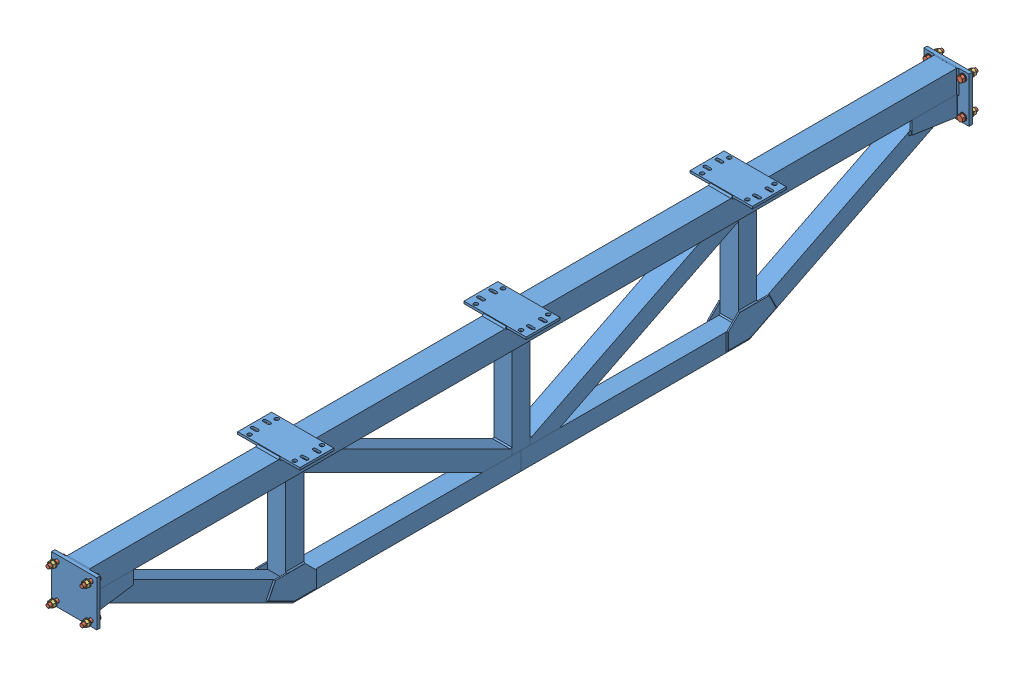
SolidWorks assembly 0404-FRAME 2 ASSEMBLAGE, configuration Predeterminado. Lengths in mm.
Overall size (275 600 3954).
17 component instances, 3 part files, 16 mates.
Components (placement in the parent):
- 0412-FRAME 2-1: 0412-FRAME 2 [Predeterminado<Como mecanizada>] at (105.2462 274.3748 0) size (275 600 3870)
- M-16x60 DIN-6914-18 and DIN-6916-1: M-16x60 DIN-6914-18 and DIN-6916 [DIN 6914 - M20 x 65 x 31-N] at (30.2462 299.3748 1904) x (0 0 1) z (-1 0 0) size (73 30 30)
- M-16x60 DIN-6914-18 and DIN-6916-6: M-16x60 DIN-6914-18 and DIN-6916 [DIN 6914 - M20 x 65 x 31-N] at (180.2462 299.3748 1904) x (0 0 1) z (-1 0 0) size (73 30 30)
- M-16x60 DIN-6914-18 and DIN-6916-8: M-16x60 DIN-6914-18 and DIN-6916 [DIN 6914 - M20 x 65 x 31-N] at (180.2462 149.3748 1904) x (0 0 1) z (-1 0 0) size (73 30 30)
- M-16x60 DIN-6914-18 and DIN-6916-10: M-16x60 DIN-6914-18 and DIN-6916 [DIN 6914 - M20 x 65 x 31-N] at (30.2462 149.3748 1904) x (0 0 1) z (-1 0 0) size (73 30 30)
- M-16x60 DIN-6914-18 and DIN-6916-11: M-16x60 DIN-6914-18 and DIN-6916 [DIN 6914 - M20 x 65 x 31-N] at (30.2462 299.3748 -1904) x (0 0 -1) z (-1 0 0) size (73 30 30)
- M-16x60 DIN-6914-18 and DIN-6916-12: M-16x60 DIN-6914-18 and DIN-6916 [DIN 6914 - M20 x 65 x 31-N] at (180.2462 299.3748 -1904) x (0 0 -1) z (-1 0 0) size (73 30 30)
- M-16x60 DIN-6914-18 and DIN-6916-13: M-16x60 DIN-6914-18 and DIN-6916 [DIN 6914 - M20 x 65 x 31-N] at (30.2462 149.3748 -1904) x (0 0 -1) z (-1 0 0) size (73 30 30)
- M-16x60 DIN-6914-18 and DIN-6916-14: M-16x60 DIN-6914-18 and DIN-6916 [DIN 6914 - M20 x 65 x 31-N] at (180.2462 149.3748 -1904) x (0 0 -1) z (-1 0 0) size (73 30 30)
- M-16 DIN-6915 and DIN-6916-1: M-16 DIN-6915 and DIN-6916 [Hexagon Nut DIN 6915 - M20 - N] at (30.2462 299.3748 1953) x (1 0 0) z (0 0 -1) size (30 30 16)
- M-16 DIN-6915 and DIN-6916-6: M-16 DIN-6915 and DIN-6916 [Hexagon Nut DIN 6915 - M20 - N] at (180.2462 299.3748 1953) x (1 0 0) z (0 0 -1) size (30 30 16)
- M-16 DIN-6915 and DIN-6916-8: M-16 DIN-6915 and DIN-6916 [Hexagon Nut DIN 6915 - M20 - N] at (30.2462 149.3748 1953) x (1 0 0) z (0 0 -1) size (30 30 16)
- M-16 DIN-6915 and DIN-6916-10: M-16 DIN-6915 and DIN-6916 [Hexagon Nut DIN 6915 - M20 - N] at (180.2462 149.3748 1953) x (1 0 0) z (0 0 -1) size (30 30 16)
- M-16 DIN-6915 and DIN-6916-5: M-16 DIN-6915 and DIN-6916 [Hexagon Nut DIN 6915 - M20 - N] at (30.2462 299.3748 -1953) x (-1 0 0) z (0 0 1) size (30 30 16)
- M-16 DIN-6915 and DIN-6916-9: M-16 DIN-6915 and DIN-6916 [Hexagon Nut DIN 6915 - M20 - N] at (30.2462 149.3748 -1953) x (-1 0 0) z (0 0 1) size (30 30 16)
- M-16 DIN-6915 and DIN-6916-7: M-16 DIN-6915 and DIN-6916 [Hexagon Nut DIN 6915 - M20 - N] at (180.2462 299.3748 -1953) x (-1 0 0) z (0 0 1) size (30 30 16)
- M-16 DIN-6915 and DIN-6916-11: M-16 DIN-6915 and DIN-6916 [Hexagon Nut DIN 6915 - M20 - N] at (180.2462 149.3748 -1953) x (-1 0 0) z (0 0 1) size (30 30 16)
Mates (geometry in assembly coordinates):
- Coincidente1: coincident anti-aligned: plane of 0412-FRAME 2-1 through (205.2462 124.3748 1920) normal (0 0 -1); plane of M-16x60 DIN-6914-18 and DIN-6916-1 through (30.2462 299.3748 1920) normal (0 0 1)
- Concéntrica1: concentric aligned: cylinder of 0412-FRAME 2-1 through (30.2462 299.3748 1935) axis (0 0 -1) radius 9; cylinder of M-16x60 DIN-6914-18 and DIN-6916-1 through (30.2462 299.3748 1904) axis (0 0 -1) radius 8
- Coincidente2: coincident anti-aligned: plane of 0412-FRAME 2-1 through (205.2462 124.3748 1920) normal (0 0 -1); plane of M-16x60 DIN-6914-18 and DIN-6916-6 through (180.2462 299.3748 1920) normal (0 0 1)
- Concéntrica2: concentric aligned: cylinder of 0412-FRAME 2-1 through (180.2462 299.3748 1935) axis (0 0 -1) radius 9; cylinder of M-16x60 DIN-6914-18 and DIN-6916-6 through (180.2462 299.3748 1904) axis (0 0 -1) radius 8
- Coincidente3: coincident anti-aligned: plane of 0412-FRAME 2-1 through (205.2462 124.3748 1920) normal (0 0 -1); plane of M-16x60 DIN-6914-18 and DIN-6916-8 through (180.2462 149.3748 1920) normal (0 0 1)
- Concéntrica3: concentric aligned: cylinder of 0412-FRAME 2-1 through (180.2462 149.3748 1935) axis (0 0 -1) radius 9; cylinder of M-16x60 DIN-6914-18 and DIN-6916-8 through (180.2462 149.3748 1904) axis (0 0 -1) radius 8
- Coincidente4: coincident anti-aligned: plane of 0412-FRAME 2-1 through (205.2462 124.3748 1920) normal (0 0 -1); plane of M-16x60 DIN-6914-18 and DIN-6916-10 through (30.2462 149.3748 1920) normal (0 0 1)
- Concéntrica4: concentric aligned: cylinder of 0412-FRAME 2-1 through (30.2462 149.3748 1935) axis (0 0 -1) radius 9; cylinder of M-16x60 DIN-6914-18 and DIN-6916-10 through (30.2462 149.3748 1904) axis (0 0 -1) radius 8
- Distancia1: distance = 15 mm anti-aligned: plane of 0412-FRAME 2-1 through (205.2462 124.3748 1935) normal (0 0 1); plane of M-16 DIN-6915 and DIN-6916-1 through (30.2462 299.3748 1950) normal (0 0 -1)
- Concéntrica5: concentric aligned: cylinder of M-16x60 DIN-6914-18 and DIN-6916-1 through (30.2462 299.3748 1904) axis (0 0 -1) radius 8; cylinder of M-16 DIN-6915 and DIN-6916-1 through (30.2462 299.3748 1966) axis (0 0 -1) radius 8
- Distancia2: distance = 15 mm anti-aligned: plane of 0412-FRAME 2-1 through (205.2462 124.3748 1935) normal (0 0 1); plane of M-16 DIN-6915 and DIN-6916-6 through (180.2462 299.3748 1950) normal (0 0 -1)
- Concéntrica6: concentric aligned: cylinder of M-16x60 DIN-6914-18 and DIN-6916-6 through (180.2462 299.3748 1904) axis (0 0 -1) radius 8; cylinder of M-16 DIN-6915 and DIN-6916-6 through (180.2462 299.3748 1966) axis (0 0 -1) radius 8
- Distancia3: distance = 15 mm anti-aligned: plane of 0412-FRAME 2-1 through (205.2462 124.3748 1935) normal (0 0 1); plane of M-16 DIN-6915 and DIN-6916-8 through (30.2462 149.3748 1950) normal (0 0 -1)
- Concéntrica7: concentric aligned: cylinder of M-16x60 DIN-6914-18 and DIN-6916-10 through (30.2462 149.3748 1904) axis (0 0 -1) radius 8; cylinder of M-16 DIN-6915 and DIN-6916-8 through (30.2462 149.3748 1966) axis (0 0 -1) radius 8
- Distancia4: distance = 15 mm anti-aligned: plane of 0412-FRAME 2-1 through (205.2462 124.3748 1935) normal (0 0 1); plane of M-16 DIN-6915 and DIN-6916-10 through (180.2462 149.3748 1950) normal (0 0 -1)
- Concéntrica8: concentric aligned: cylinder of M-16x60 DIN-6914-18 and DIN-6916-8 through (180.2462 149.3748 1904) axis (0 0 -1) radius 8; cylinder of M-16 DIN-6915 and DIN-6916-10 through (180.2462 149.3748 1966) axis (0 0 -1) radius 8
